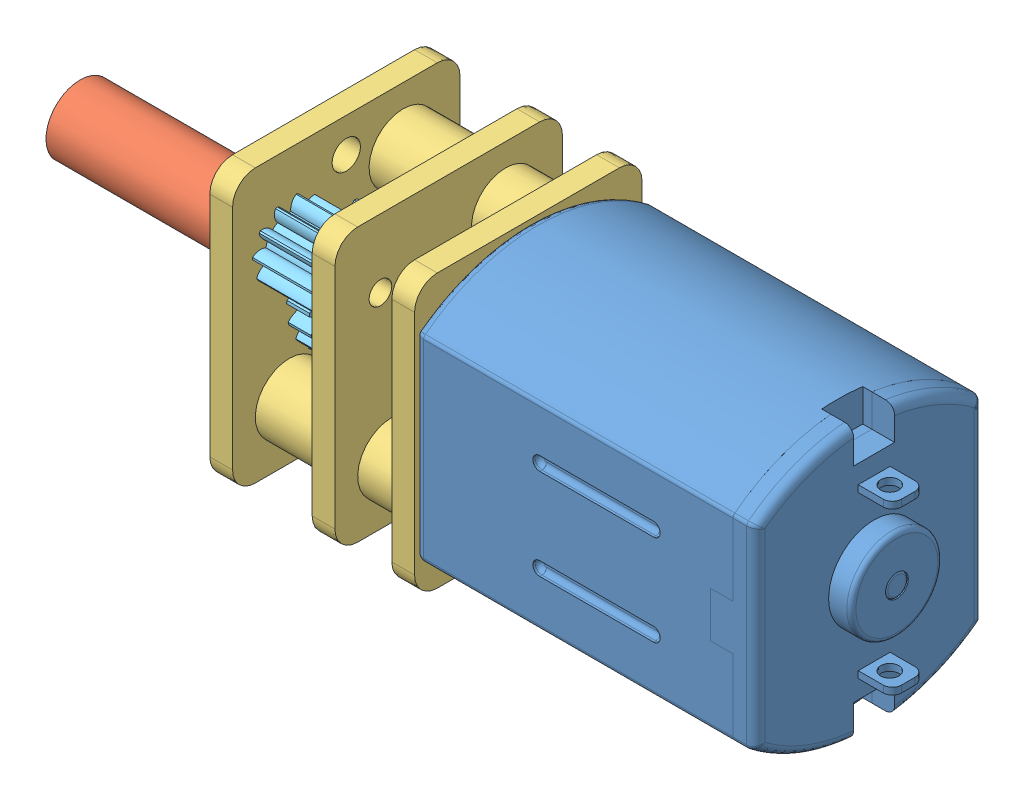
SolidWorks assembly motor, configuration Default. Lengths in mm.
Overall size (36.2 12.14 10.87).
13 component instances, 6 part files, 3 mates.
Components (placement in the parent):
- n20 motor-1: n20 motor [轴长10mm] at (15.6201 19.3513 29.2403) size (36.2 12.14 10.87)
  - motor-1: motor [默认] at (-3.4114 0.0905 -5.0483) size (19.5 12 10)
  - n20_shaft-1: n20_shaft [10mm] at (-13.1114 0.0905 -0.0483) x (0 -0.096252 -0.995357) z (0 0.995357 -0.096252) size (3 12 3)
  - n20_gearbox-1: n20_gearbox [默认] at (-11.4114 0.0905 -0.0483) x (0 1 0) z (-1 0 0) size (12 10 9.7)
  - cross recessed countersunk head screws gb1-1: cross recessed countersunk head screws gb1 [GB_CROSS_SCREWS_TYPE4 M1.6X3-2  H type-N] at (-12.4614 -3.4095 2.4517) size (3 2.7 2.7)
  - cross recessed countersunk head screws gb1-2: cross recessed countersunk head screws gb1 [GB_CROSS_SCREWS_TYPE4 M1.6X3-2  H type-N] at (-12.4614 3.5905 -2.5483) x (1 0 0) z (0 0.116872 0.993147) size (3 2.7 2.7)
  - spur gear_gb-1: spur gear_gb [GB - Spur gear 0.25M 10T 20PA 2FW ---S10A75H50L1.0N] at (-8.4114 -2.9095 -2.5483) x (1 0 0) z (0 -0.845955 0.533254) size (2 2.87 3)
  - spur gear_gb-2: spur gear_gb [GB - Spur gear 0.25M 10T 20PA 2FW ---S10A75H50L1.0N] at (-4.4114 0.0905 -0.0483) x (-1 0 0) z (0 0.404067 -0.914729) size (2 2.87 3)
  - spur gear_gb-4: spur gear_gb [GB - Spur gear 0.25M 16T 20PA 2FW ---S16A75H50L1.0N] at (-6.4114 -2.9095 -2.5483) x (1 0 0) z (0 -0.712706 0.701463) size (2 4.44 4.44)
  - spur gear_gb-6: spur gear_gb [GB - Spur gear 0.25M 19T 20PA 2FW ---S19A75H50L1.0N] at (-9.9114 0.0905 -0.0483) x (1 0 0) z (0 0.321468 -0.94692) size (2 5.22 5.24)
  - spur gear_gb-8: spur gear_gb [GB - Spur gear 0.25M 11T 20PA 3FW ---S11A75H50L1.0N] at (-10.9114 3.0905 2.9517) x (1 0 0) z (0 -0.604063 0.796937) size (3 3.2 3.23)
  - spur gear_gb-10: spur gear_gb [GB - Spur gear 0.25M 19T 20PA 1FW ---S19A75H50L1.0N] at (-11.4114 0.0905 -0.0483) x (1 0 0) z (0 -0.330889 0.94367) size (1 5.22 5.24)
- encoder-1: encoder [Default] at (29.2087 25.4418 28.9909) x (0 0 -1) z (-1 0 0) (suppressed, hidden)
Mates (geometry in assembly coordinates):
- Concentric1: concentric: circle of n20 motor-1/motor-1; circle of encoder-1
- Coincident1: coincident: plane of n20 motor-1/motor-1 through (27.2087 13.4418 34.192) normal (1 0 0); plane of encoder-1 through (27.2087 25.4418 28.9909) normal (-1 0 0)
- Parallel1: parallel aligned: plane of n20 motor-1/motor-1 through (12.2087 19.4418 34.192) normal (0 0 1); plane of encoder-1 through (32.2087 25.4418 37.9909) normal (0 0 1)
